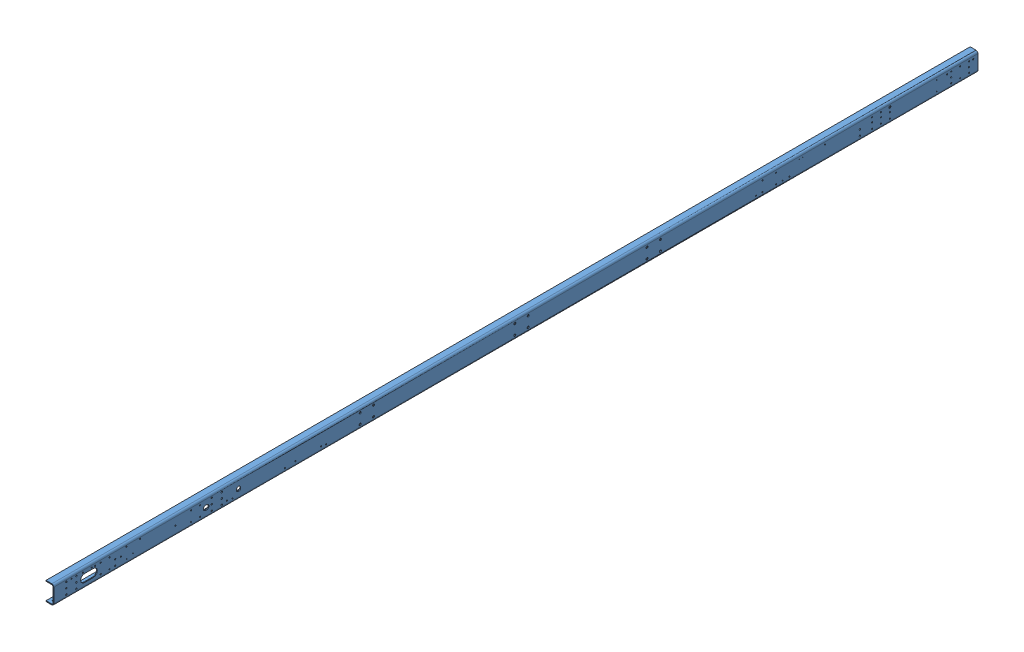
SolidWorks assembly 4128-CC1, configuration LH Rail Only. Lengths in mm.
Overall size (88.9 209.55 10515.6).
2 component instances, 1 part files, 6 mates.
Components (placement in the parent):
- 1500-CC1-3: 1500-CC1 [1500-CC1-414] at (434.975 0 1257.3)
- 1500-CC1-5: 1500-CC1 [1500-CC1-414] at (-434.975 0 -9258.3) x (-1 0 0) z (0 0 -1) (suppressed, hidden)
Mates (geometry in assembly coordinates):
- Coincident1: coincident aligned: 
- Coincident2: coincident aligned: 
- Coincident3: coincident aligned: 
- Coincident4: coincident anti-aligned: 
- Coincident5: coincident anti-aligned: 
- Coincident6: coincident aligned: 
